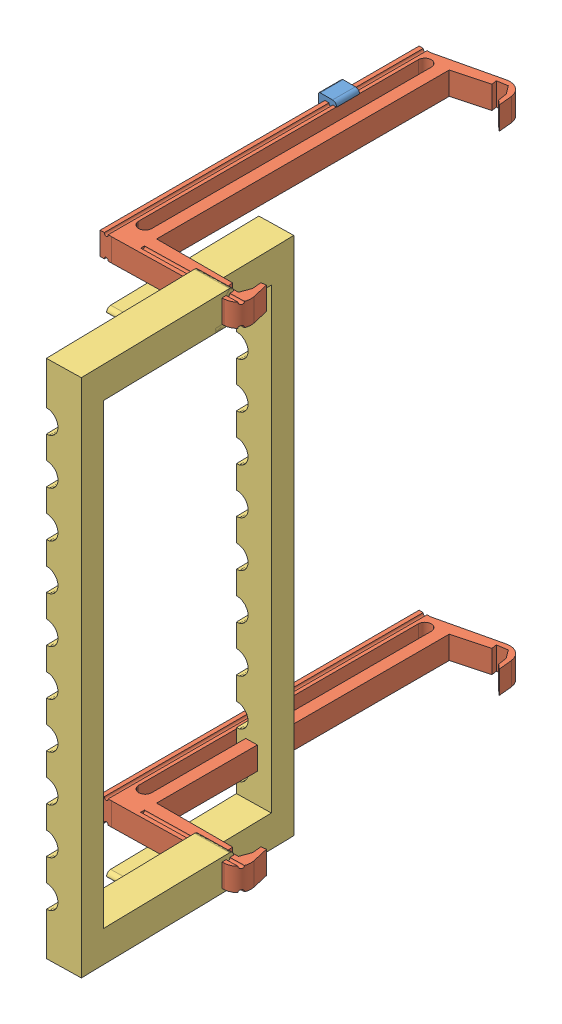
SolidWorks assembly Assem1, configuration Default. Lengths in mm.
Overall size (63.38 252.1 209.5).
5 component instances, 3 part files, 8 mates.
Components (placement in the parent):
- Part1_Bottom_4p-1: Part1_Bottom_4p [Default] at (0.4864 -1.0785 13.9434) size (11.67 22 10)
- Part2_Extreme_2p-1: Part2_Extreme_2p [Default] at (19.0164 19.0715 113.234) x (0 -1 0) z (0 0 1) size (10.17 60.53 147.33)
- Part1_Back_2p-1: Part1_Back_2p [Default] at (55.7309 20.9215 124.1084) x (-0.020593 0 -0.999788) z (-0.999788 0 0.020593) size (68 227.4 15)
- Part2_Extreme_2p-3: Part2_Extreme_2p [Default] at (19.0164 -194.6285 113.234) x (0 -1 0) z (0 0 1) size (10.17 60.53 147.33)
- Part1_Back_2p-4: Part1_Back_2p [Default] at (26.0662 -231.1793 119.0182) x (0.020593 0 0.999788) z (-0.999788 0 0.020593) size (68 227.4 15)
Mates (geometry in assembly coordinates):
- Concentric5: concentric aligned: cylinder of Part1_Bottom_4p-1 through (5.9864 9.2215 23.9434) axis (0 0 -1) radius 0.85; cylinder of Part2_Extreme_2p-1 through (5.9864 9.2215 473.5345) axis (0 0 -1) radius 0.85
- Concentric6: concentric aligned: cylinder of Part1_Bottom_4p-1 through (5.9864 18.9215 23.9434) axis (0 0 -1) radius 0.85; cylinder of Part2_Extreme_2p-1 through (5.9864 18.9215 315.9227) axis (0 0 -1) radius 0.85
- Concentric7: concentric aligned: cylinder of Part2_Extreme_2p-1 through (17.0443 18.9215 119.4041) axis (0.999788 0 -0.020593) radius 0.85; cylinder of Part1_Back_2p-1 through (40.6208 18.9215 118.9185) axis (0.999788 0 -0.020593) radius 0.85
- Concentric8: concentric aligned: cylinder of Part2_Extreme_2p-1 through (17.0443 9.2215 119.4041) axis (0.999788 0 -0.020593) radius 0.85; cylinder of Part1_Back_2p-1 through (40.6208 9.2215 118.9185) axis (0.999788 0 -0.020593) radius 0.85
- Concentric16: concentric aligned: cylinder of Part1_Back_2p-1 through (40.6208 -204.4785 118.9185) axis (0.999788 0 -0.020593) radius 0.85; cylinder of Part2_Extreme_2p-3 through (17.0443 -204.4785 119.4041) axis (0.999788 0 -0.020593) radius 0.85
- Coincident20: coincident aligned: plane of Part2_Extreme_2p-1 through (3.3364 9.0715 122.234) normal (-1 0 0); plane of Part2_Extreme_2p-3 through (3.3364 -204.6285 122.234) normal (-1 0 0)
- Coincident23: coincident anti-aligned: plane of Part1_Back_2p-1 through (41.9697 20.9215 184.4046) normal (0.020593 0 0.999788); plane of Part1_Back_2p-3 through (30.3237 -225.2044 184.6445) normal (-0.020593 0 -0.999788)
- Coincident24: coincident aligned: plane of Part2_Extreme_2p-3 through (56.466 -204.6285 121.2426) normal (0.020593 0 0.999788); plane of Part1_Back_2p-4 through (11.1281 -231.1793 122.1765) normal (0.020593 0 0.999788)
